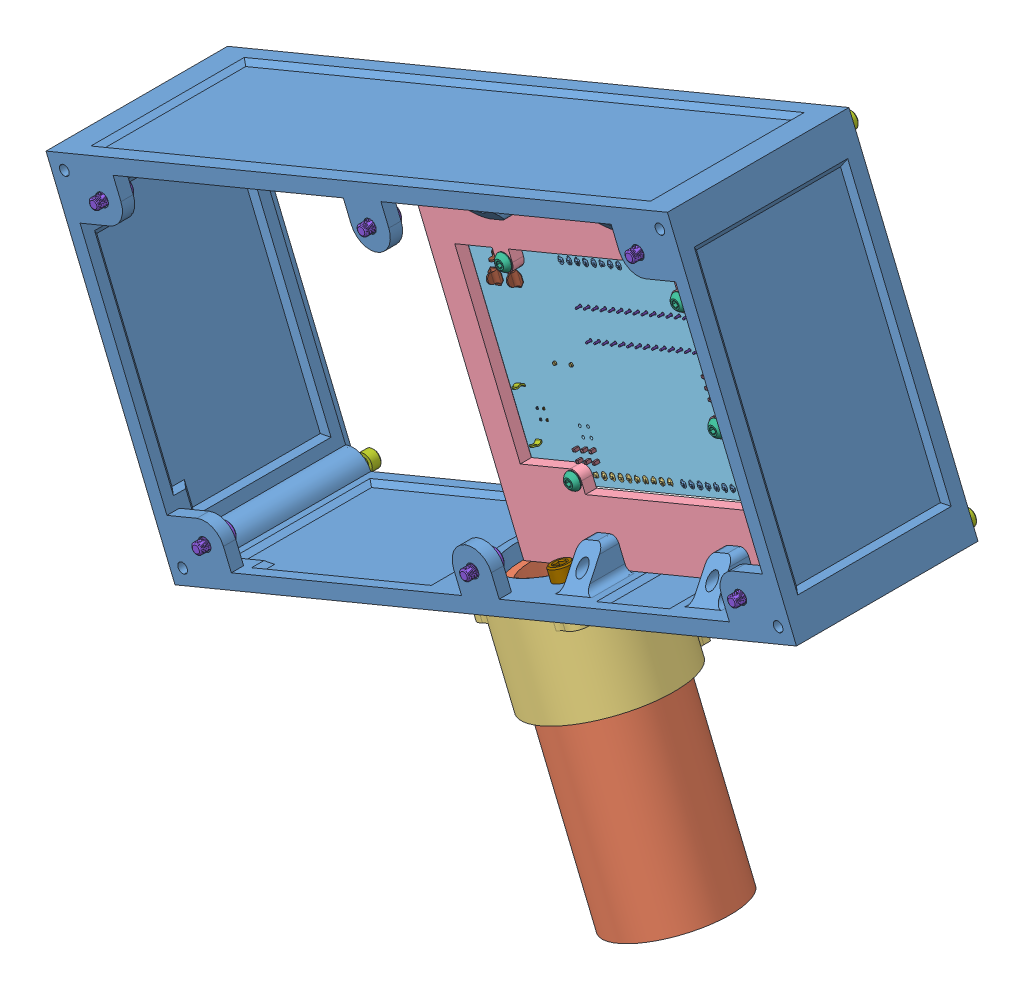
SolidWorks assembly Head Rework, configuration Default. Lengths in mm.
Overall size (213.64 204.17 57.02).
132 component instances, 47 part files, 56 mates.
Components (placement in the parent):
- head back plate-1: head back plate [Default] at (71.9097 144.0361 139.4958) x (0.923728 0.383049 0) z (0 0 1) size (188.8 93.1 3.17) (hidden)
- head base-1: head base [Default] at (71.9171 144.0391 191.1708) x (-0.923728 -0.383049 0) z (0 0 -1) size (191.52 95.88 51.67)
- 3in PVC Pipe-1: 3in PVC Pipe [Default] at (90.2814 99.7533 166.1708) x (0.383049 -0.923728 0) z (0.833223 0.345518 0.431691) size (76.2 33.4 33.4)
- PVC Clamping Hub-1: PVC Clamping Hub [Default] at (100.4973 75.1175 166.1708) x (-0.923728 -0.383049 0) z (0 0 -1) size (39.77 26.79 42.81)
- LED Matrix-1: LED Matrix [Default] at (2.0703 62.4867 191.1708) x (0.923728 0.383049 0) z (0 0 1) size (190.5 96.52 13.21) (hidden)
- arduino plate-1: arduino plate [Default] at (112.3302 160.7975 171.4958) x (-0.923728 -0.383049 0) z (0 0 1) size (85.1 87 3.17)
- arduino uno-1: arduino uno [Default] at (65.1935 170.069 169.8458) x (-0.383049 0.923728 0) z (-0.923728 -0.383049 0) size (53.34 15.25 74.93)
  - arduino_uno_board-1: arduino_uno_board [Default] at origin size (53.34 1.65 68.58)
  - 47uf CAP Dcase-1: 47uf CAP Dcase [Default] at (-9.4141 0 -18.4991) x (0 0 -1) z (1 0 0) size (6.6 5.81 8)
  - USB type b-1: USB type b [Default] at (-38.02 0.43 6.35) size (13.72 15.2 16.5)
    - USB SHELL-1: USB SHELL [Default] at origin size (13.72 15.2 16.5)
    - USB core-1: USB core [Default] at origin size (11.3 10.68 15.75)
    - usb top contact-1: usb top contact [Default] at (1.25 6.09 -0.38) size (1 9.67 13.76)
    - usb btm contact-1: usb btm contact [Default] at (1.25 4.41 -0.38) size (1 6.84 11.76)
    - usb btm contact-2: usb btm contact [Default] at (-1.25 4.41 -0.38) size (1 6.84 11.76)
    - usb top contact-2: usb top contact [Default] at (-1.25 6.09 -0.38) size (1 9.67 13.76)
  - power jack-1: power jack [Default] at (-7.675 0 1.905) size (11.2 15.2 15.9)
  - 47uf CAP Dcase-2: 47uf CAP Dcase [Default] at (-9.4141 0 -25.7132) x (0 0 -1) z (1 0 0) size (6.6 5.81 8)
  - crystal-1: crystal [Default] at (-26.162 0 -18.923) x (1 0 0) z (0 0 -1) size (4 5 11)
  - 2pin_header__02-1: 2pin_header__02 [Default] at (-46.23 0 -15.75) size (5 11.75 2.54)
  - nano - reg-1: nano - reg [Default] at (-17.399 0 -7.747) size (6.5 1.69 8.3)
  - led-1: led [Default] at (-34.29 0 -27.94) x (0 0 1) z (-1 0 0) size (4 0.9 1.55)
  - 2pin_header__02-2: 2pin_header__02 [Default] at (-30.43 0 -64.91) x (0 0 1) z (-1 0 0) size (5 11.75 2.54)
  - dip28-1: dip28 [Default] at (-16.383 1.5 -46.355) x (0 0 -1) z (1 0 0) size (35.48 7.37 10.1)
    - dip28-1: dip28 [Default] at origin size (35.48 2.8 10.1)
    - dip socket pin-1: dip socket pin [Default] at (16.51 2.8 -3.81) size (1.7 7.37 1.7)
    - dip socket pin-2: dip socket pin [Default] at (16.51 2.8 3.81) size (1.7 7.37 1.7)
    - dip socket pin-3: dip socket pin [Default] at (13.97 2.8 -3.81) size (1.7 7.37 1.7)
    - dip socket pin-4: dip socket pin [Default] at (13.97 2.8 3.81) size (1.7 7.37 1.7)
    - dip socket pin-5: dip socket pin [Default] at (11.43 2.8 -3.81) size (1.7 7.37 1.7)
    - dip socket pin-6: dip socket pin [Default] at (11.43 2.8 3.81) size (1.7 7.37 1.7)
    - dip socket pin-7: dip socket pin [Default] at (8.89 2.8 -3.81) size (1.7 7.37 1.7)
    - dip socket pin-8: dip socket pin [Default] at (8.89 2.8 3.81) size (1.7 7.37 1.7)
    - dip socket pin-9: dip socket pin [Default] at (6.35 2.8 -3.81) size (1.7 7.37 1.7)
    - dip socket pin-10: dip socket pin [Default] at (6.35 2.8 3.81) size (1.7 7.37 1.7)
    - dip socket pin-11: dip socket pin [Default] at (3.81 2.8 -3.81) size (1.7 7.37 1.7)
    - dip socket pin-12: dip socket pin [Default] at (3.81 2.8 3.81) size (1.7 7.37 1.7)
    - dip socket pin-13: dip socket pin [Default] at (1.27 2.8 -3.81) size (1.7 7.37 1.7)
    - dip socket pin-14: dip socket pin [Default] at (1.27 2.8 3.81) size (1.7 7.37 1.7)
    - dip socket pin-15: dip socket pin [Default] at (-1.27 2.8 -3.81) size (1.7 7.37 1.7)
    - dip socket pin-16: dip socket pin [Default] at (-1.27 2.8 3.81) size (1.7 7.37 1.7)
    - dip socket pin-17: dip socket pin [Default] at (-3.81 2.8 -3.81) size (1.7 7.37 1.7)
    - dip socket pin-18: dip socket pin [Default] at (-3.81 2.8 3.81) size (1.7 7.37 1.7)
    - dip socket pin-19: dip socket pin [Default] at (-6.35 2.8 -3.81) size (1.7 7.37 1.7)
    - dip socket pin-20: dip socket pin [Default] at (-6.35 2.8 3.81) size (1.7 7.37 1.7)
    - dip socket pin-21: dip socket pin [Default] at (-8.89 2.8 -3.81) size (1.7 7.37 1.7)
    - dip socket pin-22: dip socket pin [Default] at (-8.89 2.8 3.81) size (1.7 7.37 1.7)
    - dip socket pin-23: dip socket pin [Default] at (-11.43 2.8 -3.81) size (1.7 7.37 1.7)
    - dip socket pin-24: dip socket pin [Default] at (-11.43 2.8 3.81) size (1.7 7.37 1.7)
    - dip socket pin-25: dip socket pin [Default] at (-13.97 2.8 -3.81) size (1.7 7.37 1.7)
    - dip socket pin-26: dip socket pin [Default] at (-13.97 2.8 3.81) size (1.7 7.37 1.7)
    - dip socket pin-27: dip socket pin [Default] at (-16.51 2.8 -3.81) size (1.7 7.37 1.7)
    - dip socket pin-28: dip socket pin [Default] at (-16.51 2.8 3.81) size (1.7 7.37 1.7)
  - 2pin_header__02-3: 2pin_header__02 [Default] at (-27.89 0 -64.91) x (0 0 1) z (-1 0 0) size (5 11.75 2.54)
  - 2pin_header__02-4: 2pin_header__02 [Default] at (-25.35 0 -64.91) x (0 0 1) z (-1 0 0) size (5 11.75 2.54)
  - 2pin_header__02-5: 2pin_header__02 [Default] at (-46.23 0 -18.29) size (5 11.75 2.54)
  - 2pin_header__02-6: 2pin_header__02 [Default] at (-46.23 0 -20.83) size (5 11.75 2.54)
  - atmega16u2-1: atmega16u2 [Default] at (-34.671 0.06 -20) x (1 0 0) z (0 0 -1) size (5.5 1.01 5.5)
  - led-2: led [Default] at (-36.83 0 -27.94) x (0 0 1) z (-1 0 0) size (4 0.9 1.55)
  - led-3: led [Default] at (-42.037 0 -27.94) x (0 0 1) z (-1 0 0) size (4 0.9 1.55)
  - led-4: led [Default] at (-36.576 0 -58.42) x (0 0 1) z (-1 0 0) size (4 0.9 1.55)
  - 8 PORT HEADER-1: 8 PORT HEADER [Default] at (-50.8 0 -45.72) x (0 0 -1) z (1 0 0) size (20.32 10.51 2.41)
  - 8 PORT HEADER-2: 8 PORT HEADER [Default] at (-2.54 0 -27.94) x (0 0 -1) z (1 0 0) size (20.32 10.51 2.41)
  - 6 PORT HEADER-1: 6 PORT HEADER [Default] at (-2.54 0 -50.8) x (0 0 -1) z (1 0 0) size (15.24 10.51 2.41)
  - 10 PORT HEADER-1: 10 PORT HEADER [Default] at (-50.8 0 -18.796) x (0 0 -1) z (1 0 0) size (25.4 10.51 2.41)
  - ATMEL328P-1: ATMEL328P [Default] at (-16.383 4.3 -46.355) x (0 0 -1) z (1 0 0) size (35 7.27 7.87)
  - 102 RESISTOR PACK-1: 102 RESISTOR PACK [Default] at (-33.782 0 -58.42) size (3.2 0.51 3)
  - 102 RESISTOR PACK-2: 102 RESISTOR PACK [Default] at (-39.37 0 -27.94) size (3.2 0.51 3)
  - 103 RESISTOR PACK-1: 103 RESISTOR PACK [Default] at (-23.876 0 -27.94) size (3.2 0.51 3)
  - 220 RESISTOR PACK-1: 220 RESISTOR PACK [Default] at (-36.83 0 -12.827) size (3.2 0.51 3)
  - 16mhz crystal - measured-1: 16mhz crystal - measured [Default] at (-24.892 0 -41.275) x (0 0 -1) z (1 0 0) size (3.4 0.8 2.01)
  - PADS001-1: PADS001 [Default] at (-39.878 0.1 -18.288) x (-1 0 0) z (0 0 1) size (4.54 0.1 4.54)
  - 603 cap on pad-1: 603 cap on pad [Default] at (-44.45 0 -27.94) x (0 0 -1) z (1 0 0) size (2.76 0.9 1.02)
  - ssot3-1: ssot3 [Default] at (-26.5 0 -8.128) x (-1 0 0) z (0 0 -1) size (3 1.13 3.09)
  - 603 cap on pad-2: 603 cap on pad [Default] at (-29.845 0 -27.94) x (0 0 -1) z (1 0 0) size (2.76 0.9 1.02)
  - 603 cap on pad-3: 603 cap on pad [Default] at (-31.496 0 -27.94) x (0 0 -1) z (1 0 0) size (2.76 0.9 1.02)
  - lmv358-1: lmv358 [Default] at (-15.24 0 -21.971) x (0 0 -1) z (1 0 0) size (3.7 1.4 2.9)
  - 603 cap on pad-4: 603 cap on pad [Default] at (-15.24 0 -18.415) size (2.76 0.9 1.02)
  - 603 cap on pad-5: 603 cap on pad [Default] at (-29.845 0 -12.065) x (0 0 1) z (-1 0 0) size (2.76 0.9 1.02)
  - 603 cap on pad-6: 603 cap on pad [Default] at (-29.591 0 -22.352) x (0 0 1) z (-1 0 0) size (2.76 0.9 1.02)
  - 603 cap on pad-7: 603 cap on pad [Default] at (-29.591 0 -16.002) x (0 0 1) z (-1 0 0) size (2.76 0.9 1.02)
  - 603 cap on pad-8: 603 cap on pad [Default] at (-41.91 0 -12.7) x (0 0 1) z (-1 0 0) size (2.76 0.9 1.02)
  - lp2985dgkr-1: lp2985dgkr [Default] at (-20.32 0 -19.05) x (0 0 -1) z (1 0 0) size (5.85 1.1 3)
  - cd1206 diode-1: cd1206 diode [Default] at (-27.94 0 -59.436) x (0 0 -1) z (1 0 0) size (2.08 0.96 5)
  - cd1206 diode-2: cd1206 diode [Default] at (-46.228 0 -13.081) x (0 0 1) z (-1 0 0) size (2.08 0.96 5)
  - 603 resistor-1: 603 resistor [Default] at (-29.591 0 -19.05) x (0 0 1) z (-1 0 0) size (2.36 0.62 1.04)
  - blm21-1: blm21 [Default] at (-45.085 0 -7.62) x (0 0 -1) z (1 0 0) size (2.78 0.95 1.32)
  - m7 diode-1: m7 diode [Default] at (-2.794 0 -21.59) x (0 0 -1) z (1 0 0) size (6.66 2.35 2.5)
  - MLC0603-1: MLC0603 [Default] at (-33.655 0 -12.827) x (0 0 -1) z (1 0 0) size (2.36 0.6 1.04)
  - MLC0603-2: MLC0603 [Default] at (-39.37 0 -12.827) x (0 0 -1) z (1 0 0) size (2.36 0.6 1.04)
  - RESET BUTTON-1: RESET BUTTON [Default] at (-49.403 0 -6.35) size (6.2 3.1 9.6)
    - RESET CORE-1: RESET CORE [Default] at (0 0.1 0) x (-1 0 0) z (0 0 -1) size (6.2 3.1 9.6)
    - RESET-1: RESET [Default] at (0 0.1 0) x (0 0 1) z (-1 0 0) size (7.3 2 6.2)
- 93365A120_HEAT-SET INSERTS FOR PLASTICS-1: 93365A120_HEAT-SET INSERTS FOR PLASTICS [93365A120] at (139.8444 219.7779 142.6708) x (1 0 0) z (0 1 0) size (4.37 3.82 4.37)
- 93365A120_HEAT-SET INSERTS FOR PLASTICS-2: 93365A120_HEAT-SET INSERTS FOR PLASTICS [93365A120] at (115.6006 205.1236 174.6708) x (1 0 0) z (0 1 0) size (4.37 3.82 4.37)
- 93365A120_HEAT-SET INSERTS FOR PLASTICS-3: 93365A120_HEAT-SET INSERTS FOR PLASTICS [93365A120] at (173.5083 138.5969 142.6708) x (1 0 0) z (0 1 0) size (4.37 3.82 4.37)
- 93365A120_HEAT-SET INSERTS FOR PLASTICS-4: 93365A120_HEAT-SET INSERTS FOR PLASTICS [93365A120] at (-29.6736 149.4826 142.6708) x (1 0 0) z (0 1 0) size (4.37 3.82 4.37)
- 93365A120_HEAT-SET INSERTS FOR PLASTICS-5: 93365A120_HEAT-SET INSERTS FOR PLASTICS [93365A120] at (3.9903 68.3017 142.6708) x (1 0 0) z (0 1 0) size (4.37 3.82 4.37)
- 93365A120_HEAT-SET INSERTS FOR PLASTICS-6: 93365A120_HEAT-SET INSERTS FOR PLASTICS [93365A120] at (146.0051 131.8027 174.6708) x (1 0 0) z (0 1 0) size (4.37 3.82 4.37)
- 93365A120_HEAT-SET INSERTS FOR PLASTICS-7: 93365A120_HEAT-SET INSERTS FOR PLASTICS [93365A120] at (78.6468 189.7997 174.6708) x (1 0 0) z (0 1 0) size (4.37 3.82 4.37)
- 93365A120_HEAT-SET INSERTS FOR PLASTICS-8: 93365A120_HEAT-SET INSERTS FOR PLASTICS [93365A120] at (109.0513 116.4788 174.6708) x (1 0 0) z (0 1 0) size (4.37 3.82 4.37)
- 95947A005_ALUM FEM THRDED HEX STANDOFF-1: 95947A005_ALUM FEM THRDED HEX STANDOFF [95947A005] at (139.8178 162.5178 164.8458) x (-0.923728 -0.383049 0) z (0 0 -1) size (4.5 5.2 10.35)
- 95947A005_ALUM FEM THRDED HEX STANDOFF-2: 95947A005_ALUM FEM THRDED HEX STANDOFF [95947A005] at (129.1154 188.3268 164.8458) x (-0.923728 -0.383049 0) z (0 0 -1) size (4.5 5.2 10.35)
- 95947A005_ALUM FEM THRDED HEX STANDOFF-3: 95947A005_ALUM FEM THRDED HEX STANDOFF [95947A005] at (79.071 173.074 164.8458) x (-0.923728 -0.383049 0) z (0 0 -1) size (4.5 5.2 10.35)
- 95947A005_ALUM FEM THRDED HEX STANDOFF-4: 95947A005_ALUM FEM THRDED HEX STANDOFF [95947A005] at (98.73 128.9813 164.8458) x (-0.923728 -0.383049 0) z (0 0 -1) size (4.5 5.2 10.35)
- Arduino Sheild Hat-1: Arduino Sheild Hat [Default] at (65.1935 170.069 158.1958) x (-0.383049 0.923728 0) z (-0.923728 -0.383049 0) size (53.34 1.65 68.58)
- 92095A458_18-8 SS BUTTON-HEAD SOCKET CAP SCREW-1: 92095A458_18-8 SS BUTTON-HEAD SOCKET CAP SCREW [92095A458] at (129.1154 188.3268 176.1708) size (4.5 4.5 7.75)
- 92095A458_18-8 SS BUTTON-HEAD SOCKET CAP SCREW-2: 92095A458_18-8 SS BUTTON-HEAD SOCKET CAP SCREW [92095A458] at (79.071 173.074 156.6958) x (0.923728 0.383049 0) z (0 0 -1) size (4.5 4.5 7.75)
- 92095A458_18-8 SS BUTTON-HEAD SOCKET CAP SCREW-3: 92095A458_18-8 SS BUTTON-HEAD SOCKET CAP SCREW [92095A458] at (139.8178 162.5178 176.1708) size (4.5 4.5 7.75)
- 92095A458_18-8 SS BUTTON-HEAD SOCKET CAP SCREW-4: 92095A458_18-8 SS BUTTON-HEAD SOCKET CAP SCREW [92095A458] at (98.73 128.9813 156.6958) x (0.923728 0.383049 0) z (0 0 -1) size (4.5 4.5 7.75)
- 92095A458_18-8 SS BUTTON-HEAD SOCKET CAP SCREW-5: 92095A458_18-8 SS BUTTON-HEAD SOCKET CAP SCREW [92095A458] at (129.1154 188.3268 156.6958) x (0.923728 0.383049 0) z (0 0 -1) size (4.5 4.5 7.75)
- 92095A458_18-8 SS BUTTON-HEAD SOCKET CAP SCREW-6: 92095A458_18-8 SS BUTTON-HEAD SOCKET CAP SCREW [92095A458] at (139.8178 162.5178 156.6958) x (0.923728 0.383049 0) z (0 0 -1) size (4.5 4.5 7.75)
- 92095A458_18-8 SS BUTTON-HEAD SOCKET CAP SCREW-7: 92095A458_18-8 SS BUTTON-HEAD SOCKET CAP SCREW [92095A458] at (79.071 173.074 176.1708) size (4.5 4.5 7.75)
- 92095A458_18-8 SS BUTTON-HEAD SOCKET CAP SCREW-8: 92095A458_18-8 SS BUTTON-HEAD SOCKET CAP SCREW [92095A458] at (98.73 128.9813 176.1708) size (4.5 4.5 7.75)
- 4-40_SHCS-1: 4-40_SHCS [4-40 SHCS X .250] at (139.8296 219.7717 145.8458) x (-0.99949 -0.031924 0) z (0 0 -1) size (4.65 4.65 9.19)
- 4-40_SHCS-2: 4-40_SHCS [4-40 SHCS X .250] at (115.6006 205.1236 177.8458) x (-0.923728 -0.383049 0) z (0 0 -1) size (4.65 4.65 9.19)
- 4-40_SHCS-3: 4-40_SHCS [4-40 SHCS X .250] at (173.4935 138.5908 145.8458) x (-0.99949 -0.031924 0) z (0 0 -1) size (4.65 4.65 9.19)
- 4-40_SHCS-4: 4-40_SHCS [4-40 SHCS X .250] at (-29.6883 149.4765 145.8458) x (-0.99949 -0.031924 0) z (0 0 -1) size (4.65 4.65 9.19)
- 4-40_SHCS-5: 4-40_SHCS [4-40 SHCS X .250] at (3.9755 68.2956 145.8458) x (-0.99949 -0.031924 0) z (0 0 -1) size (4.65 4.65 9.19)
- 4-40_SHCS-6: 4-40_SHCS [4-40 SHCS X .250] at (146.0051 131.8027 177.8458) x (-0.923728 -0.383049 0) z (0 0 -1) size (4.65 4.65 9.19)
- 4-40_SHCS-7: 4-40_SHCS [4-40 SHCS X .250] at (78.6468 189.7997 177.8458) x (-0.923728 -0.383049 0) z (0 0 -1) size (4.65 4.65 9.19)
- 4-40_SHCS-8: 4-40_SHCS [4-40 SHCS X .250] at (109.0513 116.4788 177.8458) x (-0.923728 -0.383049 0) z (0 0 -1) size (4.65 4.65 9.19)
- 90751A110_METRIC FINE-THREAD 18-18 SS SOCKET HEAD SCREW-1: 90751A110_METRIC FINE-THREAD 18-18 SS SOCKET HEAD SCREW [90751A110] at (-18.9308 147.6125 193.6708) size (5.5 5.5 9.14)
- 90751A110_METRIC FINE-THREAD 18-18 SS SOCKET HEAD SCREW-2: 90751A110_METRIC FINE-THREAD 18-18 SS SOCKET HEAD SCREW [90751A110] at (10.2575 77.2244 193.6708) size (5.5 5.5 9.14)
- 90751A110_METRIC FINE-THREAD 18-18 SS SOCKET HEAD SCREW-3: 90751A110_METRIC FINE-THREAD 18-18 SS SOCKET HEAD SCREW [90751A110] at (57.3229 179.2332 193.6708) size (5.5 5.5 9.14)
- 90751A110_METRIC FINE-THREAD 18-18 SS SOCKET HEAD SCREW-4: 90751A110_METRIC FINE-THREAD 18-18 SS SOCKET HEAD SCREW [90751A110] at (86.5112 108.8451 193.6708) size (5.5 5.5 9.14)
- 90751A110_METRIC FINE-THREAD 18-18 SS SOCKET HEAD SCREW-5: 90751A110_METRIC FINE-THREAD 18-18 SS SOCKET HEAD SCREW [90751A110] at (133.5767 210.8539 193.6708) size (5.5 5.5 9.14)
- 90751A110_METRIC FINE-THREAD 18-18 SS SOCKET HEAD SCREW-6: 90751A110_METRIC FINE-THREAD 18-18 SS SOCKET HEAD SCREW [90751A110] at (162.765 140.4658 193.6708) size (5.5 5.5 9.14)
- 6-32_SHCS-1: 6-32_SHCS [6-32 SHCS X .250] at (78.7386 92.4227 179.6412) x (0.46775 0.193965 0.862315) z (-0.383049 0.923728 0) size (5.74 5.74 9.86)
- 6-32_SHCS-2: 6-32_SHCS [6-32 SHCS X .250] at (78.7386 92.4227 152.7004) x (-0.796545 -0.330309 0.506372) z (-0.383049 0.923728 0) size (5.74 5.74 9.86)
- 6-32_SHCS-3: 6-32_SHCS [6-32 SHCS X .250] at (103.6245 102.7423 152.7004) x (-0.46775 -0.193965 -0.862315) z (-0.383049 0.923728 0) size (5.74 5.74 9.86)
- 6-32_SHCS-4: 6-32_SHCS [6-32 SHCS X .250] at (103.6245 102.7423 179.6412) x (0.796545 0.330309 -0.506372) z (-0.383049 0.923728 0) size (5.74 5.74 9.86)
Mates (geometry in assembly coordinates):
- Coincident1: coincident anti-aligned: plane of head base-1 through (71.9171 144.0391 191.1708) normal (0 0 1); plane of LED Matrix-1 through (2.0703 62.4867 191.1708) normal (0 0 -1)
- Coincident2: coincident aligned: plane of head base-1 through (1.8271 63.0733 187.6708) normal (-0.923728 -0.383049 0); plane of LED Matrix-1 through (2.0703 62.4867 203.8708) normal (-0.923728 -0.383049 0)
- Coincident3: coincident aligned: plane of head base-1 through (-34.9016 151.6449 187.6708) normal (-0.383049 0.923728 0); plane of LED Matrix-1 through (-34.9016 151.6449 203.8708) normal (-0.383049 0.923728 0)
- Concentric3: concentric anti-aligned: cylinder of arduino plate-1 through (115.6006 205.1236 174.6708) axis (0 0 -1) radius 1.45; cone of head base-1 through (115.6006 205.1236 174.6708) axis (0 0 1)
- Concentric4: concentric anti-aligned: cone of head base-1 through (109.0598 116.4715 174.6708) axis (0 0 1); cylinder of arduino plate-1 through (109.0598 116.4715 174.6708) axis (0 0 -1) radius 1.45
- Concentric5: concentric aligned: cylinder of arduino plate-1 through (129.1154 188.3268 174.6708) axis (0 0 -1) radius 1.45; cylinder of arduino uno-1/arduino_uno_board-1 through (129.1154 188.3268 171.4958) axis (0 0 -1) radius 1.5875
- Coincident10: coincident anti-aligned: plane of arduino plate-1 through (112.3302 160.7975 171.4958) normal (0 0 -1); plane of arduino uno-1/arduino_uno_board-1 through (65.1935 170.069 171.4958) normal (0 0 1)
- Coincident12: coincident anti-aligned: plane of head base-1 through (80.4875 195.1639 174.6708) normal (0 0 -1); plane of arduino plate-1 through (112.3302 160.7975 174.6708) normal (0 0 1)
- Parallel7: parallel anti-aligned: plane of arduino plate-1 through (139.1645 171.9251 174.6708) normal (-0.923728 -0.383049 0); plane of arduino uno-1/arduino_uno_board-1 through (146.6284 146.0939 171.4958) normal (0.923728 0.383049 0)
- Concentric8: concentric aligned: cylinder of head base-1 through (53.5524 188.3259 166.1708) axis (0.383049 -0.923728 0) radius 15.5; cylinder of PVC Clamping Hub-1 through (90.2814 99.7533 166.1708) axis (0.383049 -0.923728 0) radius 16.7005
- Concentric9: concentric anti-aligned: cylinder of head base-1 through (65.9953 193.4857 152.7004) axis (0.383049 -0.923728 0) radius 1.8986; cylinder of PVC Clamping Hub-1 through (105.1567 99.0474 152.7004) axis (-0.383049 0.923728 0) radius 3.1852
- Coincident15: coincident aligned: plane of head base-1 through (1.8271 63.0733 187.6708) normal (0.383049 -0.923728 0); circle of PVC Clamping Hub-1
- Concentric10: concentric anti-aligned: cylinder of 3in PVC Pipe-1 through (119.4697 29.3652 166.1708) axis (-0.383049 0.923728 0) radius 16.7005; cylinder of PVC Clamping Hub-1 through (90.2814 99.7533 166.1708) axis (0.383049 -0.923728 0) radius 16.7005
- Coincident16: coincident anti-aligned: plane of head base-1 through (1.8271 63.0733 187.6708) normal (0.383049 -0.923728 0); plane of 3in PVC Pipe-1 through (90.2814 99.7533 166.1708) normal (-0.383049 0.923728 0)
- Coincident17: coincident anti-aligned: plane of head back plate-1 through (71.9097 144.0361 142.6708) normal (0 0 1); plane of head base-1 through (71.9171 144.0391 142.6708) normal (0 0 -1)
- Concentric11: concentric anti-aligned: cylinder of head back plate-1 through (-29.6745 149.4822 142.6708) axis (0 0 -1) radius 1.45; cone of head base-1 through (-29.6745 149.4822 142.6708) axis (0 0 1)
- Coincident18: coincident anti-aligned: plane of head back plate-1 through (2.5407 64.8767 142.6708) normal (-0.923728 -0.383049 0); plane of head base-1 through (2.557 64.8374 139.4958) normal (0.923728 0.383049 0)
- Concentric13: concentric aligned: cylinder of head base-1 through (139.8444 219.7779 191.1718) axis (0 0 -1) radius 1.3833; cylinder of 93365A120_HEAT-SET INSERTS FOR PLASTICS-1 through (139.8444 219.7779 142.6708) axis (0 0 -1) radius 1.9431
- Coincident19: coincident aligned: circle of head base-1; plane of 93365A120_HEAT-SET INSERTS FOR PLASTICS-1 through (139.8444 219.7779 142.6708) normal (0 0 -1)
- Concentric14: concentric aligned: cylinder of head base-1 through (115.6006 205.1236 191.1708) axis (0 0 -1) radius 1.6925; cylinder of 93365A120_HEAT-SET INSERTS FOR PLASTICS-2 through (115.6006 205.1236 174.6708) axis (0 0 -1) radius 1.9431
- Coincident20: coincident aligned: plane of head base-1 through (117.4366 210.4858 174.6708) normal (0 0 -1); plane of 93365A120_HEAT-SET INSERTS FOR PLASTICS-2 through (115.6006 205.1236 174.6708) normal (0 0 -1)
- Coincident21: coincident anti-aligned: plane of arduino uno-1/arduino_uno_board-1 through (65.1935 170.069 169.8458) normal (0 0 -1); plane of 95947A005_ALUM FEM THRDED HEX STANDOFF-1 through (138.8226 164.9177 169.8458) normal (0 0 1)
- Coincident22: coincident anti-aligned: plane of arduino uno-1/arduino_uno_board-1 through (65.1935 170.069 169.8458) normal (0 0 -1); plane of 95947A005_ALUM FEM THRDED HEX STANDOFF-2 through (128.1202 190.7267 169.8458) normal (0 0 1)
- Coincident23: coincident anti-aligned: plane of arduino uno-1/arduino_uno_board-1 through (65.1935 170.069 169.8458) normal (0 0 -1); plane of 95947A005_ALUM FEM THRDED HEX STANDOFF-3 through (78.0758 175.4739 169.8458) normal (0 0 1)
- Coincident24: coincident anti-aligned: plane of arduino uno-1/arduino_uno_board-1 through (65.1935 170.069 169.8458) normal (0 0 -1); plane of 95947A005_ALUM FEM THRDED HEX STANDOFF-4 through (97.7348 131.3812 169.8458) normal (0 0 1)
- Concentric15: concentric aligned: cylinder of arduino uno-1/arduino_uno_board-1 through (98.73 128.9813 171.4958) axis (0 0 -1) radius 1.5875; line of 95947A005_ALUM FEM THRDED HEX STANDOFF-4 through (98.73 128.9813 170.5328) axis (0 0 -1)
- Concentric16: concentric aligned: cylinder of arduino uno-1/arduino_uno_board-1 through (79.071 173.074 171.4958) axis (0 0 -1) radius 1.5875; line of 95947A005_ALUM FEM THRDED HEX STANDOFF-3 through (79.071 173.074 170.5328) axis (0 0 -1)
- Concentric17: concentric aligned: cylinder of arduino uno-1/arduino_uno_board-1 through (129.1154 188.3268 171.4958) axis (0 0 -1) radius 1.5875; line of 95947A005_ALUM FEM THRDED HEX STANDOFF-2 through (129.1154 188.3268 170.5328) axis (0 0 -1)
- Concentric18: concentric aligned: cylinder of arduino uno-1/arduino_uno_board-1 through (139.8178 162.5178 171.4958) axis (0 0 -1) radius 1.5875; line of 95947A005_ALUM FEM THRDED HEX STANDOFF-1 through (139.8178 162.5178 170.5328) axis (0 0 -1)
- Concentric19: concentric aligned: cylinder of arduino uno-1/arduino_uno_board-1 through (129.1154 188.3268 171.4958) axis (0 0 -1) radius 1.5875; cylinder of Arduino Sheild Hat-1 through (129.1154 188.3268 159.8458) axis (0 0 -1) radius 1.5875
- Concentric20: concentric aligned: cylinder of arduino uno-1/arduino_uno_board-1 through (139.8178 162.5178 171.4958) axis (0 0 -1) radius 1.5875; cylinder of Arduino Sheild Hat-1 through (139.8178 162.5178 159.8458) axis (0 0 -1) radius 1.5875
- Coincident25: coincident anti-aligned: plane of 95947A005_ALUM FEM THRDED HEX STANDOFF-2 through (128.1202 190.7267 159.8458) normal (0 0 -1); plane of Arduino Sheild Hat-1 through (65.1935 170.069 159.8458) normal (0 0 1)
- Concentric21: concentric anti-aligned: cylinder of 92095A458_18-8 SS BUTTON-HEAD SOCKET CAP SCREW-3 through (139.8178 162.5178 168.6708) axis (0 0 -1) radius 1.25; cylinder of 92095A458_18-8 SS BUTTON-HEAD SOCKET CAP SCREW-6 through (139.8178 162.5178 164.1958) axis (0 0 1) radius 1.25
- Concentric22: concentric aligned: cylinder of 92095A458_18-8 SS BUTTON-HEAD SOCKET CAP SCREW-3 through (139.8178 162.5178 168.6708) axis (0 0 -1) radius 1.25; cylinder of Arduino Sheild Hat-1 through (139.8178 162.5178 159.8458) axis (0 0 -1) radius 1.5875
- Concentric23: concentric aligned: cylinder of Arduino Sheild Hat-1 through (129.1154 188.3268 159.8458) axis (0 0 -1) radius 1.5875; cylinder of 92095A458_18-8 SS BUTTON-HEAD SOCKET CAP SCREW-1 through (129.1154 188.3268 168.6708) axis (0 0 -1) radius 1.25
- Concentric24: concentric anti-aligned: cylinder of Arduino Sheild Hat-1 through (129.1154 188.3268 159.8458) axis (0 0 -1) radius 1.5875; cylinder of 92095A458_18-8 SS BUTTON-HEAD SOCKET CAP SCREW-5 through (129.1154 188.3268 164.1958) axis (0 0 1) radius 1.25
- Concentric25: concentric aligned: cylinder of Arduino Sheild Hat-1 through (79.071 173.074 159.8458) axis (0 0 -1) radius 1.5875; cylinder of 92095A458_18-8 SS BUTTON-HEAD SOCKET CAP SCREW-7 through (79.071 173.074 168.6708) axis (0 0 -1) radius 1.25
- Concentric26: concentric anti-aligned: cylinder of Arduino Sheild Hat-1 through (79.071 173.074 159.8458) axis (0 0 -1) radius 1.5875; cylinder of 92095A458_18-8 SS BUTTON-HEAD SOCKET CAP SCREW-2 through (79.071 173.074 164.1958) axis (0 0 1) radius 1.25
- Concentric27: concentric anti-aligned: cylinder of Arduino Sheild Hat-1 through (98.73 128.9813 159.8458) axis (0 0 -1) radius 1.5875; cylinder of 92095A458_18-8 SS BUTTON-HEAD SOCKET CAP SCREW-4 through (98.73 128.9813 164.1958) axis (0 0 1) radius 1.25
- Concentric28: concentric aligned: cylinder of Arduino Sheild Hat-1 through (98.73 128.9813 159.8458) axis (0 0 -1) radius 1.5875; cylinder of 92095A458_18-8 SS BUTTON-HEAD SOCKET CAP SCREW-8 through (98.73 128.9813 168.6708) axis (0 0 -1) radius 1.25
- Coincident26: coincident anti-aligned: plane of Arduino Sheild Hat-1 through (65.1935 170.069 158.1958) normal (0 0 -1); plane of 92095A458_18-8 SS BUTTON-HEAD SOCKET CAP SCREW-4 through (97.8682 131.0597 158.1958) normal (0 0 1)
- Coincident28: coincident anti-aligned: plane of Arduino Sheild Hat-1 through (65.1935 170.069 158.1958) normal (0 0 -1); plane of 92095A458_18-8 SS BUTTON-HEAD SOCKET CAP SCREW-2 through (78.2091 175.1523 158.1958) normal (0 0 1)
- Coincident29: coincident anti-aligned: plane of Arduino Sheild Hat-1 through (65.1935 170.069 158.1958) normal (0 0 -1); plane of 92095A458_18-8 SS BUTTON-HEAD SOCKET CAP SCREW-5 through (128.2535 190.4052 158.1958) normal (0 0 1)
- Coincident30: coincident anti-aligned: plane of Arduino Sheild Hat-1 through (65.1935 170.069 158.1958) normal (0 0 -1); plane of 92095A458_18-8 SS BUTTON-HEAD SOCKET CAP SCREW-6 through (138.9559 164.5962 158.1958) normal (0 0 1)
- Coincident31: coincident anti-aligned: plane of 92095A458_18-8 SS BUTTON-HEAD SOCKET CAP SCREW-3 through (139.8178 160.2678 174.6708) normal (0 0 -1); plane of arduino plate-1 through (112.3302 160.7975 174.6708) normal (0 0 1)
- Coincident32: coincident aligned: plane of 92095A458_18-8 SS BUTTON-HEAD SOCKET CAP SCREW-3 through (139.8178 160.2678 174.6708) normal (0 0 -1); plane of 92095A458_18-8 SS BUTTON-HEAD SOCKET CAP SCREW-1 through (129.1154 186.0768 174.6708) normal (0 0 -1)
- Coincident33: coincident aligned: plane of 92095A458_18-8 SS BUTTON-HEAD SOCKET CAP SCREW-3 through (139.8178 160.2678 174.6708) normal (0 0 -1); plane of 92095A458_18-8 SS BUTTON-HEAD SOCKET CAP SCREW-8 through (98.73 126.7313 174.6708) normal (0 0 -1)
- Coincident34: coincident aligned: plane of 92095A458_18-8 SS BUTTON-HEAD SOCKET CAP SCREW-3 through (139.8178 160.2678 174.6708) normal (0 0 -1); plane of 92095A458_18-8 SS BUTTON-HEAD SOCKET CAP SCREW-7 through (79.071 170.824 174.6708) normal (0 0 -1)
- Concentric29: concentric anti-aligned: cylinder of arduino plate-1 through (115.6006 205.1236 174.6708) axis (0 0 -1) radius 1.45; cylinder of 4-40_SHCS-2 through (115.6006 205.1236 158.7958) axis (0 0 1) radius 2.3241
- Coincident35: coincident anti-aligned: plane of arduino plate-1 through (112.3302 160.7975 171.4958) normal (0 0 -1); plane of 4-40_SHCS-2 through (115.6006 205.1236 171.4958) normal (0 0 1)
- Concentric30: concentric anti-aligned: cylinder of head back plate-1 through (139.8296 219.7717 142.6708) axis (0 0 -1) radius 1.45; cylinder of 4-40_SHCS-1 through (139.8296 219.7717 126.7958) axis (0 0 1) radius 2.3241
- Coincident36: coincident anti-aligned: plane of head back plate-1 through (71.9097 144.0361 139.4958) normal (0 0 -1); plane of 4-40_SHCS-1 through (139.8296 219.7717 139.4958) normal (0 0 1)
- Concentric32: concentric aligned: cylinder of head base-1 through (-18.9308 147.6125 187.6708) axis (0 0 1) radius 1.8; cylinder of 90751A110_METRIC FINE-THREAD 18-18 SS SOCKET HEAD SCREW-1 through (-18.9308 147.6125 184.6708) axis (0 0 1) radius 2.75
- Coincident38: coincident anti-aligned: plane of head base-1 through (71.9171 144.0391 187.6708) normal (0 0 -1); plane of 90751A110_METRIC FINE-THREAD 18-18 SS SOCKET HEAD SCREW-1 through (-18.9308 147.6125 187.6708) normal (0 0 1)
- Concentric33: concentric aligned: cylinder of head base-1 through (41.1094 183.1661 179.6412) axis (0.383049 -0.923728 0) radius 1.8986; cylinder of 6-32_SHCS-1 through (71.4415 110.0197 179.6412) axis (0.383049 -0.923728 0) radius 2.8702
- Coincident39: coincident anti-aligned: plane of head base-1 through (94.1068 105.6699 187.6708) normal (-0.383049 0.923728 0); plane of 6-32_SHCS-1 through (76.3062 98.2884 179.6412) normal (0.383049 -0.923728 0)
